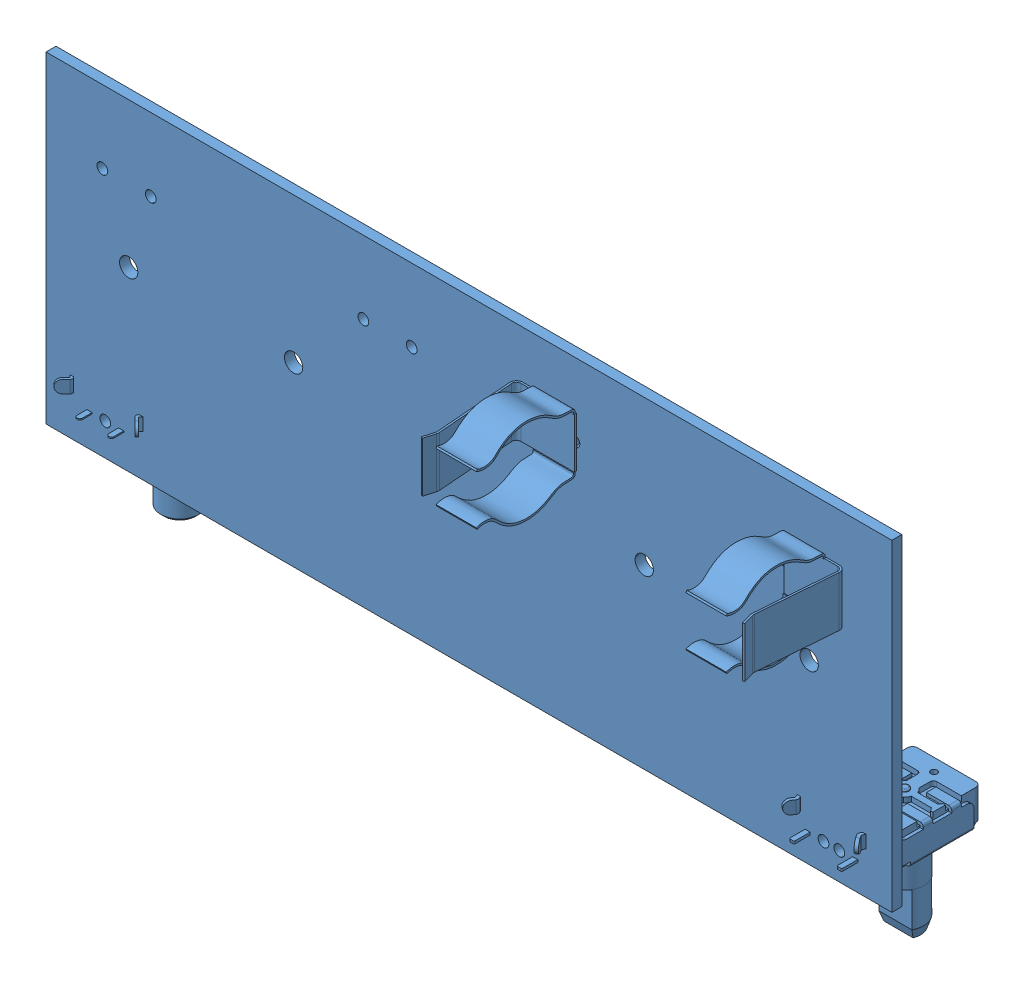
SolidWorks assembly AWK-105-0005, configuration Default. Lengths in mm.
Overall size (173.42 81.53 53.52).
4 component instances, 4 part files, 0 mates.
Components (placement in the parent):
- AWK-105-0005-1: AWK-105-0005 [Default] at (-1.3271 -0.16 0.3884) size (133.35 63.18 34.02)
- AWK-105-0022-1: AWK-105-0022 [Default] at origin
- AWK-105-0008-1: AWK-105-0008 [Default] at (-101.2269 -37.7293 23.7082) size (13.34 22.3 20.2) (hidden)
- AWK-105-0009-1: AWK-105-0009 [Default] at (-89.8645 -46.0444 10.4384) size (12.1 22.6 20.7) (hidden)
